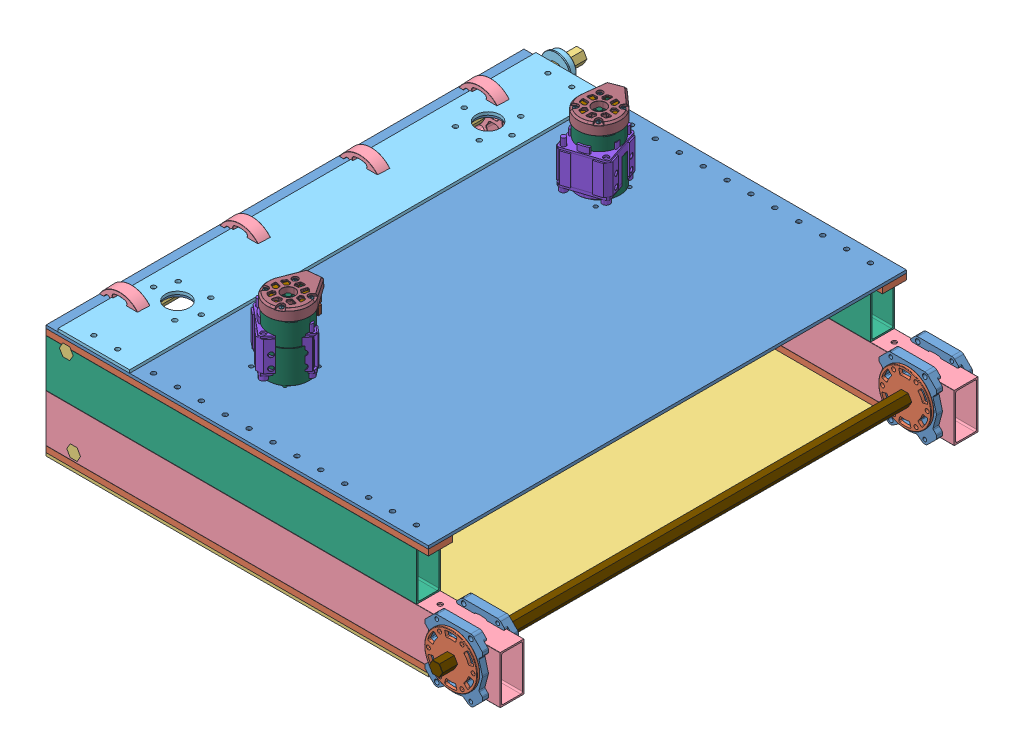
SolidWorks assembly top down new Shooter Assembly, configuration Default. Lengths in mm.
Overall size (495.19 207.94 571.5).
76 component instances, 24 part files, 95 mates.
Components (placement in the parent):
- ShooterPlate5-1: ShooterPlate5 [Default] at (-92.3523 376.6959 643.1212) size (406.4 3.17 508)
- ThickStick-3: ThickStick [Default] at (-92.3523 262.3959 643.1212) size (406.4 6.35 25.4)
- ThickStick-1: ThickStick [Default] at (-92.3523 370.3459 643.1212) size (406.4 6.35 25.4)
- ThickStick-2: ThickStick [Default] at (-92.3523 262.3959 160.5212) size (406.4 6.35 25.4)
- ThickStick-4: ThickStick [Default] at (-92.3523 370.3459 160.5212) size (406.4 6.35 25.4)
- ShooterPlate4-1: ShooterPlate4 [Default] at (-257.4523 259.2209 643.1212) size (406.4 3.17 508)
- side-1: side [Default] at (364.8477 294.1459 147.8212) x (0 0 1) z (-1 0 0) size (25.4 50.8 482.6)
- side-2: side [Default] at (364.8477 294.1459 630.4212) x (0 0 1) z (-1 0 0) size (25.4 50.8 482.6)
- Motor support2-1: Motor support2 [Default] at (-41.5523 379.8709 389.1212) x (0 0 1) z (-1 0 0) size (508 3.17 76.2)
- 4in hex stealth wheel-2: 4in hex stealth wheel [Default] at (72.733 290.5093 554.2466) x (0 -1 0) z (-0.5 0 0.866025) size (25.4 101.6 101.6)
  - 4in Wheel Intergreated Hub 500 HEX.STEP-1: 4in Wheel Intergreated Hub 500 HEX.STEP [Default] at origin size (25.4 92.71 92.71)
  - 4in Tread.STEP-1: 4in Tread.STEP [Default] at origin size (25.4 101.6 101.6)
- 4in hex stealth wheel-3: 4in hex stealth wheel [Default] at (72.7282 290.5093 224.043) x (0 -1 0) z (0.312488 0 0.949922) size (25.4 101.6 101.6)
  - 4in Wheel Intergreated Hub 500 HEX.STEP-1: 4in Wheel Intergreated Hub 500 HEX.STEP [Default] at origin size (25.4 92.71 92.71)
  - 4in Tread.STEP-1: 4in Tread.STEP [Default] at origin size (25.4 101.6 101.6)
- 4-1 Banebots-1: 4-1 Banebots [Default] at (72.7474 422.4159 224.0202) x (-0.312488 0 -0.949922) z (0 -1 0) size (47.62 47.62 76.19)
- 4-1 Banebots-2: 4-1 Banebots [Default] at (72.7471 422.4159 554.2219) x (-0.638444 0 0.769669) z (0 -1 0) size (47.62 47.62 76.19)
- 775pro.step-1: 775pro.step [Default] at (71.7936 373.6479 219.2017) x (-0.934395 0 0.356239) z (0 -1 0) size (44.99 55.15 90.45)
  - 217-6457-000 Rev2.step-1: 217-6457-000 Rev2.step [Default] at (0 0 -66.1) x (1 0 0) z (0 1 0) size (44.99 33.26 55.15)
    - 217-6457-900 Rev1.step-1: 217-6457-900 Rev1.step [Default] at (0 5.3622 0) x (-1 0 0.000693) z (0.000693 0 1) size (41.5 28.13 51.51)
      - 217-6457-901 Rev3_Instruction Config.step-1: 217-6457-901 Rev3_Instruction Config.step [Default] at origin size (41.5 2.36 51.5)
      - 30-45BBS Rev1_SHORTENED CONTACT.step-1: 30-45BBS Rev1_SHORTENED CONTACT.step [Default] at (3.95 14.4494 26.711) x (0 1 0) z (0 0 -1) size (26 3.6 2)
      - 30-45BBS Rev1_SHORTENED CONTACT.step-2: 30-45BBS Rev1_SHORTENED CONTACT.step [Default] at (-3.9748 14.4494 26.711) x (0 1 0) z (0 0 -1) size (26 3.6 2)
      - PA45XX-X Rev1.step-1: PA45XX-X Rev1.step [Default] at (-8.4198 2.3622 73.1531) x (0 1 0) z (-1 0 0) size (24.71 8.41 8.41)
      - PA45XX-X Rev1.step-2: PA45XX-X Rev1.step [Default] at (-0.495 2.3622 73.1531) x (0 1 0) z (-1 0 0) size (24.71 8.41 8.41)
    - 217-6457-001 Rev4.step-1: 217-6457-001 Rev4.step [Default] at origin size (41.49 7.8 41.49)
    - 217-6457-002 Rev7.step-1: 217-6457-002 Rev7.step [Default] at (0 0.05 0) size (44.99 11.5 55.15)
    - 217-9191-008 Rev1.step-1: 217-9191-008 Rev1.step [Default] at (81.4247 7.8 32.3804) x (-0.560945 0 -0.827853) z (0 1 0) size (4.2 4.2 11.81)
    - 217-9191-008 Rev1.step-2: 217-9191-008 Rev1.step [Default] at (32.3804 7.8 -81.4247) x (-0.827853 0 0.560945) z (0 1 0) size (4.2 4.2 11.81)
    - 217-9191-008 Rev1.step-3: 217-9191-008 Rev1.step [Default] at (-81.4247 7.8 -32.3804) x (0.560945 0 0.827853) z (0 1 0) size (4.2 4.2 11.81)
    - 217-9191-008 Rev1.step-4: 217-9191-008 Rev1.step [Default] at (-32.3804 7.8 81.4247) x (0.827853 0 -0.560945) z (0 1 0) size (4.2 4.2 11.81)
  - 217-4347-000 Rev2.step-1: 217-4347-000 Rev2.step [Default] x (0 0 -1) z (-1 0 0) size (88 44.3 44.3)
- 775pro.step-2: 775pro.step [Default] at (77.5101 373.6479 555.4281) x (-0.994351 0 0.106139) z (0 -1 0) size (44.99 55.15 90.45)
  - 217-6457-000 Rev2.step-1: 217-6457-000 Rev2.step [Default] at (0 0 -66.1) x (1 0 0) z (0 1 0) size (44.99 33.26 55.15)
    - 217-6457-900 Rev1.step-1: 217-6457-900 Rev1.step [Default] at (0 5.3622 0) x (-1 0 0.000693) z (0.000693 0 1) size (41.5 28.13 51.51)
      - 217-6457-901 Rev3_Instruction Config.step-1: 217-6457-901 Rev3_Instruction Config.step [Default] at origin size (41.5 2.36 51.5)
      - 30-45BBS Rev1_SHORTENED CONTACT.step-1: 30-45BBS Rev1_SHORTENED CONTACT.step [Default] at (3.95 14.4494 26.711) x (0 1 0) z (0 0 -1) size (26 3.6 2)
      - 30-45BBS Rev1_SHORTENED CONTACT.step-2: 30-45BBS Rev1_SHORTENED CONTACT.step [Default] at (-3.9748 14.4494 26.711) x (0 1 0) z (0 0 -1) size (26 3.6 2)
      - PA45XX-X Rev1.step-1: PA45XX-X Rev1.step [Default] at (-8.4198 2.3622 73.1531) x (0 1 0) z (-1 0 0) size (24.71 8.41 8.41)
      - PA45XX-X Rev1.step-2: PA45XX-X Rev1.step [Default] at (-0.495 2.3622 73.1531) x (0 1 0) z (-1 0 0) size (24.71 8.41 8.41)
    - 217-6457-001 Rev4.step-1: 217-6457-001 Rev4.step [Default] at origin size (41.49 7.8 41.49)
    - 217-6457-002 Rev7.step-1: 217-6457-002 Rev7.step [Default] at (0 0.05 0) size (44.99 11.5 55.15)
    - 217-9191-008 Rev1.step-1: 217-9191-008 Rev1.step [Default] at (81.4247 7.8 32.3804) x (-0.560945 0 -0.827853) z (0 1 0) size (4.2 4.2 11.81)
    - 217-9191-008 Rev1.step-2: 217-9191-008 Rev1.step [Default] at (32.3804 7.8 -81.4247) x (-0.827853 0 0.560945) z (0 1 0) size (4.2 4.2 11.81)
    - 217-9191-008 Rev1.step-3: 217-9191-008 Rev1.step [Default] at (-81.4247 7.8 -32.3804) x (0.560945 0 0.827853) z (0 1 0) size (4.2 4.2 11.81)
    - 217-9191-008 Rev1.step-4: 217-9191-008 Rev1.step [Default] at (-32.3804 7.8 81.4247) x (0.827853 0 -0.560945) z (0 1 0) size (4.2 4.2 11.81)
  - 217-4347-000 Rev2.step-1: 217-4347-000 Rev2.step [Default] x (0 0 -1) z (-1 0 0) size (88 44.3 44.3)
- 4in hex shaft-1: 4in hex shaft [Default] at (72.7477 381.6489 224.0212) x (0.666412 0 -0.745583) z (0 -1 0) size (14.66 12.7 101.6)
- 4in hex shaft-2: 4in hex shaft [Default] at (72.7477 381.6489 554.2212) x (-0.638444 0 0.769669) z (0 -1 0) size (14.66 12.7 101.6)
- am-2986 FR8ZZ Hex Bearing.step-1: am-2986 FR8ZZ Hex Bearing.step [Default] at (72.7477 255.9925 554.2212) x (0.638444 0 -0.769669) z (0 1 0) size (31.12 31.12 7.93)
- am-2986 FR8ZZ Hex Bearing.step-2: am-2986 FR8ZZ Hex Bearing.step [Default] at (72.7477 373.4675 554.2212) x (1 0 0) z (0 1 0) size (31.12 31.12 7.93)
- am-2986 FR8ZZ Hex Bearing.step-3: am-2986 FR8ZZ Hex Bearing.step [Default] at (72.7477 373.4675 224.0212) x (0.312488 0 0.949922) z (0 1 0) size (31.12 31.12 7.93)
- am-2986 FR8ZZ Hex Bearing.step-4: am-2986 FR8ZZ Hex Bearing.step [Default] at (72.7477 255.9925 224.0212) x (0.9789 0 0.204338) z (0 1 0) size (31.12 31.12 7.93)
- shooteraxle-1: shooteraxle [Default] at (347.36 295.7842 109.7212) size (14.66 12.7 558.8)
- VersaBlock V2 (217-6111).step-1: VersaBlock V2 (217-6111).step [Default] at (347.3674 295.7969 131.9462) x (1 0 0) z (0 0 -1) size (61.04 66.67 9.53)
- VersaBlock V2 (217-6111).step-2: VersaBlock V2 (217-6111).step [Default] at (347.3674 295.7969 614.5462) x (1 0 0) z (0 0 -1) size (61.04 66.67 9.53)
- VersaBlock V2 (217-6111).step-3: VersaBlock V2 (217-6111).step [Default] at (347.3674 295.7969 646.2962) x (-1 0 0) z (0 0 1) size (61.04 66.67 9.53)
- VersaBlock V2 (217-6111).step-4: VersaBlock V2 (217-6111).step [Default] at (347.3674 295.7969 163.6962) x (-1 0 0) z (0 0 1) size (61.04 66.67 9.53)
- 1_2” Hex Bore Aluminum VersaHub (217-2592).step-1: 1_2” Hex Bore Aluminum VersaHub (217-2592).step [Default] at (347.3674 295.7969 138.2962) x (0 0 -1) z (0.866025 -0.5 0) size (12.7 55.88 55.88)
- 1_2” Hex Bore Aluminum VersaHub (217-2592).step-2: 1_2” Hex Bore Aluminum VersaHub (217-2592).step [Default] at (347.3674 295.7969 157.3462) x (0 0 1) z (-0.866025 -0.5 0) size (12.7 55.88 55.88)
- 1_2” Hex Bore Aluminum VersaHub (217-2592).step-3: 1_2” Hex Bore Aluminum VersaHub (217-2592).step [Default] at (347.3674 295.7969 620.8962) x (0 0 -1) z (0.866025 0.5 0) size (12.7 55.88 55.88)
- 1_2” Hex Bore Aluminum VersaHub (217-2592).step-4: 1_2” Hex Bore Aluminum VersaHub (217-2592).step [Default] at (347.3674 295.7969 639.9462) x (0 0 1) z (-0.866025 0.5 0) size (12.7 55.88 55.88)
- axel and wheels for top down new Shooter design-1: axel and wheels for top down new Shooter design [Default] at origin size (69.37 69.37 546.1)
  - .5in hex shaft 21.5in-1: .5in hex shaft 21.5in [Default] at (-70.8055 365.9874 135.1212) size (14.66 12.7 546.1)
  - 2in complient wheel-1: 2in complient wheel [Default] at (-70.2556 366.9399 192.2712) x (0.5 -0.866025 0) z (0 0 1) size (50.78 50.78 12.7)
  - 2in complient wheel-2: 2in complient wheel [Default] at (-70.2556 366.9399 446.2712) size (50.78 50.78 12.7)
  - 2in complient wheel-3: 2in complient wheel [Default] at (-71.3555 366.9399 573.2712) size (50.78 50.78 12.7)
  - 2in complient wheel-4: 2in complient wheel [Default] at (-70.2556 366.9399 319.2712) size (50.78 50.78 12.7)
- 2in complient wheel-5: 2in complient wheel [Default] at (-62.4291 278.0399 319.2712) size (50.78 50.78 12.7)
- 2in complient wheel-6: 2in complient wheel [Default] at (-62.4291 278.0399 446.2712) size (50.78 50.78 12.7)
- 2in complient wheel-7: 2in complient wheel [Default] at (-63.529 278.0399 573.2712) size (50.78 50.78 12.7)
- 2in complient wheel-8: 2in complient wheel [Default] at (-62.4291 278.0399 192.2712) x (0.5 -0.866025 0) z (0 0 1) size (50.78 50.78 12.7)
- .5in hex shaft 21.5in-2: .5in hex shaft 21.5in [Default] at (-62.9791 277.0874 135.1212) size (14.66 12.7 546.1)
- Hex Bearing-1: Hex Bearing [Default] at (-70.8055 365.9874 115.1734) size (31.12 31.12 7.93)
- side short v2-1: side short v2 [Default] at (390.2477 344.9459 630.4212) x (0 0 1) z (-1 0 0) size (25.4 50.8 393.7)
- side short v2-2: side short v2 [Default] at (390.2477 344.9459 147.8212) x (0 0 1) z (-1 0 0) size (25.4 50.8 393.7)
Mates (geometry in assembly coordinates):
- Coincident2: coincident aligned: plane of ShooterPlate5-1 through (-92.3523 379.8709 643.1212) normal (-1 0 0); plane of side-2 through (-92.3523 319.2919 642.8672) normal (-1 0 0)
- Coincident5: coincident aligned: plane of ShooterPlate5-1 through (314.0477 379.8709 643.1212) normal (1 0 0); plane of ThickStick-1 through (314.0477 376.6959 643.1212) normal (1 0 0)
- Coincident6: coincident aligned: plane of ShooterPlate5-1 through (-92.3523 379.8709 643.1212) normal (0 0 1); plane of ThickStick-1 through (-92.3523 376.6959 643.1212) normal (0 0 1)
- Coincident8: coincident anti-aligned: plane of ThickStick-3 through (-92.3523 268.7459 643.1212) normal (0 1 0); plane of side-2 through (390.2477 268.7459 642.8672) normal (0 -1 0)
- Coincident9: coincident aligned: plane of ThickStick-3 through (-92.3523 268.7459 643.1212) normal (0 0 1); plane of side-2 through (390.2477 319.2919 643.1212) normal (0 0 1)
- Coincident11: coincident aligned: plane of ThickStick-1 through (-92.3523 376.6959 643.1212) normal (-1 0 0); plane of ThickStick-3 through (-92.3523 268.7459 643.1212) normal (-1 0 0)
- Coincident12: coincident anti-aligned: plane of ThickStick-3 through (-92.3523 262.3959 643.1212) normal (0 -1 0); plane of ShooterPlate4-1 through (-257.4523 262.3959 643.1212) normal (0 1 0)
- Coincident13: coincident aligned: plane of ShooterPlate5-1 through (-92.3523 379.8709 643.1212) normal (0 0 1); plane of ShooterPlate4-1 through (-257.4523 262.3959 643.1212) normal (0 0 1)
- Coincident14: coincident aligned: plane of ThickStick-3 through (314.0477 268.7459 643.1212) normal (1 0 0); plane of ShooterPlate4-1 through (314.0477 262.3959 643.1212) normal (1 0 0)
- Coincident16: coincident aligned: plane of ShooterPlate5-1 through (-92.3523 379.8709 643.1212) normal (-1 0 0); plane of ThickStick-4 through (-92.3523 376.6959 160.5212) normal (-1 0 0)
- Coincident18: coincident aligned: plane of ShooterPlate5-1 through (-92.3523 379.8709 135.1212) normal (0 0 -1); plane of ThickStick-4 through (-92.3523 376.6959 135.1212) normal (0 0 -1)
- Coincident19: coincident aligned: plane of ThickStick-4 through (-92.3523 376.6959 135.1212) normal (0 0 -1); plane of side-1 through (390.2477 268.9999 135.1212) normal (0 0 -1)
- Coincident20: coincident aligned: plane of ThickStick-4 through (-92.3523 376.6959 160.5212) normal (-1 0 0); plane of side-1 through (-92.3523 319.2919 160.2672) normal (-1 0 0)
- Coincident21: coincident anti-aligned: plane of ThickStick-2 through (-92.3523 262.3959 160.5212) normal (0 -1 0); plane of ShooterPlate4-1 through (-257.4523 262.3959 643.1212) normal (0 1 0)
- Coincident22: coincident aligned: plane of ThickStick-2 through (-92.3523 268.7459 135.1212) normal (0 0 -1); plane of side-1 through (390.2477 268.9999 135.1212) normal (0 0 -1)
- Coincident23: coincident aligned: plane of ShooterPlate5-1 through (-92.3523 379.8709 643.1212) normal (-1 0 0); plane of ThickStick-2 through (-92.3523 268.7459 160.5212) normal (-1 0 0)
- Coincident24: coincident anti-aligned: plane of ShooterPlate5-1 through (-92.3523 379.8709 643.1212) normal (0 1 0); plane of Motor support2-1 through (-41.5523 379.8709 389.1212) normal (0 -1 0)
- Coincident25: coincident aligned: plane of side-1 through (390.2477 268.9999 135.1212) normal (0 0 -1); plane of Motor support2-1 through (-79.6523 383.0459 135.1212) normal (0 0 -1)
- Concentric1: concentric aligned: cylinder of ShooterPlate5-1 through (-41.5523 376.6959 224.0212) axis (0 1 0) radius 14.2875; cylinder of Motor support2-1 through (-41.5523 379.8709 224.0212) axis (0 1 0) radius 12.7
- Concentric10: concentric anti-aligned: cylinder of ShooterPlate5-1 through (72.7477 376.6959 224.0212) axis (0 1 0) radius 14.2875; cylinder of am-2986 FR8ZZ Hex Bearing.step-3 through (72.7477 381.3949 224.0212) axis (0 -1 0) radius 14.2875
- Coincident39: coincident anti-aligned: plane of ShooterPlate5-1 through (-92.3523 379.8709 643.1212) normal (0 1 0); plane of am-2986 FR8ZZ Hex Bearing.step-3 through (77.1132 379.8709 237.2916) normal (0 -1 0)
- Concentric11: concentric anti-aligned: cylinder of ShooterPlate5-1 through (72.7477 376.6959 554.2212) axis (0 1 0) radius 14.2875; cylinder of am-2986 FR8ZZ Hex Bearing.step-2 through (72.7477 381.3949 554.2212) axis (0 -1 0) radius 14.2875
- Coincident40: coincident anti-aligned: plane of ShooterPlate5-1 through (-92.3523 379.8709 643.1212) normal (0 1 0); plane of am-2986 FR8ZZ Hex Bearing.step-2 through (86.7177 379.8709 554.2212) normal (0 -1 0)
- Concentric12: concentric anti-aligned: cylinder of ShooterPlate4-1 through (72.7477 259.2209 554.2212) axis (0 1 0) radius 14.2875; cylinder of am-2986 FR8ZZ Hex Bearing.step-1 through (72.7477 263.9199 554.2212) axis (0 -1 0) radius 14.2875
- Coincident41: coincident anti-aligned: plane of ShooterPlate4-1 through (-257.4523 262.3959 643.1212) normal (0 1 0); plane of am-2986 FR8ZZ Hex Bearing.step-1 through (81.6668 262.3959 543.4689) normal (0 -1 0)
- Concentric13: concentric anti-aligned: cylinder of ShooterPlate4-1 through (72.7477 259.2209 224.0212) axis (0 1 0) radius 14.2875; cylinder of am-2986 FR8ZZ Hex Bearing.step-4 through (72.7477 263.9199 224.0212) axis (0 -1 0) radius 14.2875
- Coincident42: coincident anti-aligned: plane of ShooterPlate4-1 through (-257.4523 262.3959 643.1212) normal (0 1 0); plane of am-2986 FR8ZZ Hex Bearing.step-4 through (86.4229 262.3959 226.8758) normal (0 -1 0)
- Coincident44: coincident anti-aligned: plane of 4-1 Banebots-1 through (67.8613 381.6559 229.488) normal (-0.949922 0 0.312488); plane of am-2986 FR8ZZ Hex Bearing.step-3 through (67.8613 381.3949 229.488) normal (0.949922 0 -0.312488)
- Coincident53: coincident anti-aligned: plane of 4in hex shaft-2 through (75.2945 280.0489 561.097) normal (0.769669 0 0.638444); plane of am-2986 FR8ZZ Hex Bearing.step-1 through (79.9758 263.9199 555.4535) normal (-0.769669 0 -0.638444)
- Coincident54: coincident anti-aligned: plane of 4in hex shaft-2 through (68.0664 280.0489 559.8646) normal (-0.168074 0 0.985774); plane of am-2986 FR8ZZ Hex Bearing.step-1 through (75.2945 263.9199 561.097) normal (0.168074 0 -0.985774)
- Tangent9: tangent: plane of assembly; face of 4-1 Banebots-2; plane of 4in hex shaft-2 through (72.7477 381.6489 554.2212) normal (0 1 0)
- Coincident55: coincident aligned: plane of 4-1 Banebots-2 through (68.0664 381.6559 559.8646) normal (-0.937743 0 0.347331); plane of 4in hex shaft-2 through (65.5197 280.0489 552.9888) normal (-0.937743 0 0.347331)
- Coincident56: coincident aligned: plane of 4-1 Banebots-2 through (65.5197 381.6559 552.9888) normal (-0.769669 0 -0.638444); plane of 4in hex shaft-2 through (70.201 280.0489 547.3453) normal (-0.769669 0 -0.638444)
- Tangent10: tangent: plane of assembly; face of 4-1 Banebots-2; plane of am-2986 FR8ZZ Hex Bearing.step-2 through (88.3052 381.3949 554.2212) normal (0 1 0)
- Tangent11: tangent: plane of assembly; face of 4-1 Banebots-1; plane of 4in hex shaft-1 through (72.7477 381.6489 224.0212) normal (0 1 0)
- Coincident57: coincident aligned: plane of 4-1 Banebots-1 through (65.5701 381.6559 222.5229) normal (-0.745583 0 -0.666412); plane of 4in hex shaft-1 through (70.4564 280.0489 217.056) normal (-0.745583 0 -0.666412)
- Coincident58: coincident aligned: plane of 4-1 Banebots-1 through (67.8613 381.6559 229.488) normal (-0.949922 0 0.312488); plane of 4in hex shaft-1 through (65.5701 280.0489 222.5229) normal (-0.949922 0 0.312488)
- Tangent12: tangent: plane of assembly; face of 4-1 Banebots-1; plane of am-2986 FR8ZZ Hex Bearing.step-3 through (77.6092 381.3949 238.7996) normal (0 1 0)
- Coincident60: coincident anti-aligned: plane of 4in hex shaft-1 through (79.9253 280.0489 225.5194) normal (0.949922 0 -0.312488); plane of am-2986 FR8ZZ Hex Bearing.step-4 through (77.6341 263.9199 218.5543) normal (-0.949922 0 0.312488)
- Coincident61: coincident anti-aligned: plane of 4in hex shaft-1 through (75.039 280.0489 230.9863) normal (0.745583 0 0.666412); plane of am-2986 FR8ZZ Hex Bearing.step-4 through (79.9253 263.9199 225.5194) normal (-0.745583 0 -0.666412)
- Coincident62: coincident anti-aligned: plane of 4in hex stealth wheel-3/4in Wheel Intergreated Hub 500 HEX.STEP-1 through (70.4277 304.4334 217.05) normal (-0.204338 0 0.9789); plane of 4in hex shaft-1 through (77.6341 280.0489 218.5543) normal (0.204338 0 -0.9789)
- Coincident63: coincident anti-aligned: plane of 4in hex stealth wheel-3/4in Wheel Intergreated Hub 500 HEX.STEP-1 through (77.6341 304.4334 218.5543) normal (-0.949922 0 0.312488); plane of 4in hex shaft-1 through (79.9253 280.0489 225.5194) normal (0.949922 0 -0.312488)
- Distance1: distance = 25.4 mm aligned: plane of side-1 through (390.2477 268.9999 135.1212) normal (0 0 -1); plane of shooteraxle-1 through (347.36 295.7842 109.7212) normal (0 0 -1)
- Coincident72: coincident anti-aligned: plane of side-2 through (390.2477 319.2919 643.1212) normal (0 0 1); plane of VersaBlock V2 (217-6111).step-3 through (347.3674 295.7969 643.1212) normal (0 0 -1)
- Coincident73: coincident anti-aligned: plane of side-2 through (390.2477 268.7459 642.8672) normal (0 -1 0); plane of VersaBlock V2 (217-6111).step-3 through (316.8493 268.7459 722.6131) normal (0 1 0)
- Tangent13: tangent aligned: cylinder of side-2 through (345.7977 295.9239 643.1212) axis (0 0 -1) radius 12.7; cylinder of VersaBlock V2 (217-6111).step-3 through (347.3674 295.7969 604.2621) axis (0 0 1) radius 14.2748
- Coincident74: coincident anti-aligned: plane of side-2 through (390.2477 268.9999 617.7212) normal (0 0 -1); plane of VersaBlock V2 (217-6111).step-2 through (347.3674 295.7969 617.7212) normal (0 0 1)
- Coincident75: coincident anti-aligned: plane of side-2 through (390.2477 268.7459 642.8672) normal (0 -1 0); plane of VersaBlock V2 (217-6111).step-2 through (377.8855 268.7459 538.2292) normal (0 1 0)
- Concentric24: concentric anti-aligned: cylinder of VersaBlock V2 (217-6111).step-2 through (365.4542 323.1543 620.8962) axis (0 0 1) radius 2.0193; cylinder of VersaBlock V2 (217-6111).step-3 through (365.4542 323.1543 639.9462) axis (0 0 -1) radius 2.4892
- Coincident76: coincident anti-aligned: plane of side-1 through (390.2477 268.9999 135.1212) normal (0 0 -1); plane of VersaBlock V2 (217-6111).step-1 through (347.3674 295.7969 135.1212) normal (0 0 1)
- Coincident77: coincident anti-aligned: plane of side-1 through (390.2477 268.7459 160.2672) normal (0 -1 0); plane of VersaBlock V2 (217-6111).step-1 through (377.8855 268.7459 55.6292) normal (0 1 0)
- Tangent14: tangent aligned: cylinder of side-1 through (345.7977 295.9239 160.5212) axis (0 0 -1) radius 12.7; cylinder of VersaBlock V2 (217-6111).step-1 through (347.3674 295.7969 173.9802) axis (0 0 -1) radius 14.2748
- Coincident78: coincident anti-aligned: plane of side-1 through (390.2477 268.7459 160.2672) normal (0 -1 0); plane of VersaBlock V2 (217-6111).step-4 through (316.8493 268.7459 240.0131) normal (0 1 0)
- Coincident79: coincident anti-aligned: plane of side-1 through (390.2477 319.2919 160.5212) normal (0 0 1); plane of VersaBlock V2 (217-6111).step-4 through (347.3674 295.7969 160.5212) normal (0 0 -1)
- Concentric26: concentric anti-aligned: cylinder of VersaBlock V2 (217-6111).step-1 through (365.4542 323.1543 138.2962) axis (0 0 1) radius 2.0193; cylinder of VersaBlock V2 (217-6111).step-4 through (365.4542 323.1543 157.3462) axis (0 0 -1) radius 2.4892
- Coincident80: coincident anti-aligned: plane of VersaBlock V2 (217-6111).step-3 through (359.2736 316.4191 649.4712) normal (0 0 1); plane of 1_2” Hex Bore Aluminum VersaHub (217-2592).step-4 through (354.5148 308.1766 649.4712) normal (0 0 -1)
- Concentric30: concentric aligned: cylinder of VersaBlock V2 (217-6111).step-3 through (335.4611 316.4191 649.4712) axis (0 0 1) radius 1.7272; cylinder of 1_2” Hex Bore Aluminum VersaHub (217-2592).step-4 through (335.4611 316.4191 566.8528) axis (0 0 1) radius 2.15
- Concentric31: concentric aligned: cylinder of VersaBlock V2 (217-6111).step-3 through (359.2736 316.4191 649.4712) axis (0 0 1) radius 1.7272; cylinder of 1_2” Hex Bore Aluminum VersaHub (217-2592).step-4 through (359.2736 316.4191 566.8528) axis (0 0 1) radius 2.15
- Coincident82: coincident anti-aligned: plane of VersaBlock V2 (217-6111).step-1 through (335.4611 316.4191 128.7712) normal (0 0 -1); plane of 1_2” Hex Bore Aluminum VersaHub (217-2592).step-1 through (354.5148 308.1766 128.7712) normal (0 0 1)
- Concentric32: concentric aligned: cylinder of VersaBlock V2 (217-6111).step-1 through (335.4611 316.4191 128.7712) axis (0 0 -1) radius 1.7272; cylinder of 1_2” Hex Bore Aluminum VersaHub (217-2592).step-1 through (335.4611 316.4191 211.3895) axis (0 0 -1) radius 2.15
- Concentric33: concentric aligned: cylinder of VersaBlock V2 (217-6111).step-1 through (359.2736 316.4191 128.7712) axis (0 0 -1) radius 1.7272; cylinder of 1_2” Hex Bore Aluminum VersaHub (217-2592).step-1 through (359.2736 316.4191 211.3895) axis (0 0 -1) radius 2.15
- Coincident83: coincident anti-aligned: plane of VersaBlock V2 (217-6111).step-4 through (359.2736 316.4191 166.8712) normal (0 0 1); plane of 1_2” Hex Bore Aluminum VersaHub (217-2592).step-2 through (340.2199 308.1766 166.8712) normal (0 0 -1)
- Concentric35: concentric aligned: cylinder of VersaBlock V2 (217-6111).step-4 through (359.2736 316.4191 166.8712) axis (0 0 1) radius 1.7272; cylinder of 1_2” Hex Bore Aluminum VersaHub (217-2592).step-2 through (359.2736 316.4191 84.2528) axis (0 0 1) radius 2.15
- Concentric36: concentric aligned: cylinder of VersaBlock V2 (217-6111).step-4 through (335.4611 316.4191 166.8712) axis (0 0 1) radius 1.7272; cylinder of 1_2” Hex Bore Aluminum VersaHub (217-2592).step-2 through (335.4611 316.4191 84.2528) axis (0 0 1) radius 2.15
- Coincident84: coincident anti-aligned: plane of VersaBlock V2 (217-6111).step-2 through (335.4611 316.4191 611.3712) normal (0 0 -1); plane of 1_2” Hex Bore Aluminum VersaHub (217-2592).step-3 through (340.2199 308.1766 611.3712) normal (0 0 1)
- Concentric37: concentric aligned: cylinder of VersaBlock V2 (217-6111).step-2 through (359.2736 316.4191 611.3712) axis (0 0 -1) radius 1.7272; cylinder of 1_2” Hex Bore Aluminum VersaHub (217-2592).step-3 through (359.2736 316.4191 693.9895) axis (0 0 -1) radius 2.15
- Concentric38: concentric aligned: cylinder of VersaBlock V2 (217-6111).step-2 through (335.4611 316.4191 611.3712) axis (0 0 -1) radius 1.7272; cylinder of 1_2” Hex Bore Aluminum VersaHub (217-2592).step-3 through (335.4611 316.4191 693.9895) axis (0 0 -1) radius 2.15
- Coincident85: coincident anti-aligned: plane of shooteraxle-1 through (351.0262 289.4342 668.5212) normal (0 -1 0); plane of 1_2” Hex Bore Aluminum VersaHub (217-2592).step-4 through (343.6939 289.4342 639.9462) normal (0 1 0)
- Coincident86: coincident anti-aligned: plane of shooteraxle-1 through (343.6939 289.4342 668.5212) normal (-0.866025 -0.5 0); plane of 1_2” Hex Bore Aluminum VersaHub (217-2592).step-4 through (340.0204 295.7969 639.9462) normal (0.866025 0.5 0)
- Coincident105: coincident anti-aligned: plane of 2in complient wheel-8 through (-59.3129 283.4374 192.213) normal (0 -1 0); plane of .5in hex shaft 21.5in-2 through (-59.3129 283.4374 97.0212) normal (0 1 0)
- Coincident106: coincident anti-aligned: plane of 2in complient wheel-8 through (-56.1966 278.0399 192.213) normal (-0.866025 -0.5 0); plane of .5in hex shaft 21.5in-2 through (-55.6467 277.0874 97.0212) normal (0.866025 0.5 0)
- Coincident107: coincident anti-aligned: plane of 2in complient wheel-7 through (-66.6452 283.4374 573.213) normal (0.866025 -0.5 0); plane of .5in hex shaft 21.5in-2 through (-66.6452 283.4374 97.0212) normal (-0.866025 0.5 0)
- Coincident108: coincident anti-aligned: plane of 2in complient wheel-6 through (-59.3129 283.4374 446.213) normal (0 -1 0); plane of .5in hex shaft 21.5in-2 through (-59.3129 283.4374 97.0212) normal (0 1 0)
- Coincident109: coincident anti-aligned: plane of 2in complient wheel-5 through (-59.3129 283.4374 319.213) normal (0 -1 0); plane of .5in hex shaft 21.5in-2 through (-59.3129 283.4374 97.0212) normal (0 1 0)
- Distance6: distance = 184.15 mm aligned: plane of 2in complient wheel-6 through (-62.4291 278.0399 458.9712) normal (0 0 1); plane of .5in hex shaft 21.5in-2 through (-62.9791 277.0874 643.1212) normal (0 0 1)
- Distance7: distance = 57.15 mm aligned: plane of 2in complient wheel-7 through (-63.529 278.0399 585.9712) normal (0 0 1); plane of .5in hex shaft 21.5in-2 through (-62.9791 277.0874 643.1212) normal (0 0 1)
- Distance8: distance = 311.15 mm aligned: plane of 2in complient wheel-5 through (-62.4291 278.0399 331.9712) normal (0 0 1); plane of .5in hex shaft 21.5in-2 through (-62.9791 277.0874 643.1212) normal (0 0 1)
- Distance9: distance = 438.15 mm aligned: plane of 2in complient wheel-8 through (-62.4291 278.0399 204.9712) normal (0 0 1); plane of .5in hex shaft 21.5in-2 through (-62.9791 277.0874 643.1212) normal (0 0 1)
- Coincident110: coincident anti-aligned: plane of 2in complient wheel-6 through (-56.1966 278.0399 446.213) normal (-0.866025 -0.5 0); plane of .5in hex shaft 21.5in-2 through (-55.6467 277.0874 97.0212) normal (0.866025 0.5 0)
- Coincident111: coincident anti-aligned: plane of 2in complient wheel-5 through (-56.1966 278.0399 319.213) normal (-0.866025 -0.5 0); plane of .5in hex shaft 21.5in-2 through (-55.6467 277.0874 97.0212) normal (0.866025 0.5 0)
- Coincident112: coincident anti-aligned: plane of 2in complient wheel-7 through (-60.4127 283.4374 573.213) normal (0 -1 0); plane of .5in hex shaft 21.5in-2 through (-59.3129 283.4374 97.0212) normal (0 1 0)
- Distance10: distance = 38.1 mm aligned: plane of side-1 through (390.2477 268.9999 135.1212) normal (0 0 -1); plane of .5in hex shaft 21.5in-2 through (-62.9791 277.0874 97.0212) normal (0 0 -1)
- Coincident120: coincident anti-aligned: plane of side-1 through (390.2477 319.5459 135.3752) normal (0 1 0); plane of side short v2-2 through (-92.3523 319.5459 160.2672) normal (0 -1 0)
- Coincident121: coincident aligned: plane of side-1 through (390.2477 268.9999 135.1212) normal (0 0 -1); plane of side short v2-2 through (-92.3523 319.7999 135.1212) normal (0 0 -1)
- Coincident122: coincident aligned: plane of side-1 through (-92.3523 319.2919 160.2672) normal (-1 0 0); plane of side short v2-2 through (-92.3523 370.0919 160.2672) normal (-1 0 0)
- Coincident123: coincident anti-aligned: plane of side-2 through (390.2477 319.5459 617.9752) normal (0 1 0); plane of side short v2-1 through (-92.3523 319.5459 642.8672) normal (0 -1 0)
- Coincident124: coincident aligned: plane of side-2 through (390.2477 319.2919 643.1212) normal (0 0 1); plane of side short v2-1 through (-92.3523 370.0919 643.1212) normal (0 0 1)
- Coincident125: coincident aligned: plane of side-2 through (-92.3523 319.2919 642.8672) normal (-1 0 0); plane of side short v2-1 through (-92.3523 370.0919 642.8672) normal (-1 0 0)
- Coincident126: coincident anti-aligned: plane of ThickStick-4 through (-92.3523 370.3459 160.5212) normal (0 -1 0); plane of side short v2-2 through (-92.3523 370.3459 135.3752) normal (0 1 0)
- Coincident128: coincident anti-aligned: plane of ThickStick-1 through (-92.3523 370.3459 643.1212) normal (0 -1 0); plane of side short v2-1 through (-92.3523 370.3459 617.9752) normal (0 1 0)
- Coincident129: coincident anti-aligned: plane of ShooterPlate5-1 through (-92.3523 376.6959 643.1212) normal (0 -1 0); plane of ThickStick-1 through (-92.3523 376.6959 643.1212) normal (0 1 0)
- Distance14: distance = 38.1 mm aligned: plane of side-1 through (390.2477 268.9999 135.1212) normal (0 0 -1); plane of Assem1^top down new Shooter Assembly-1/.5in hex shaft 21.5in-1 through (-70.8055 365.9874 97.0212) normal (0 0 -1)
- Coincident130: coincident anti-aligned: plane of Assem1^top down new Shooter Assembly-1/.5in hex shaft 21.5in-1 through (-67.1394 372.3374 97.0212) normal (0 1 0); plane of Hex Bearing-1 through (-74.4717 372.3374 123.1007) normal (0 -1 0)
- Coincident131: coincident anti-aligned: plane of Assem1^top down new Shooter Assembly-1/.5in hex shaft 21.5in-1 through (-67.1394 359.6374 97.0212) normal (0.866025 -0.5 0); plane of Hex Bearing-1 through (-63.4732 365.9874 123.1007) normal (-0.866025 0.5 0)
- Distance15: distance = 76.2 mm anti-aligned: plane of Assem1^top down new Shooter Assembly-1/.5in hex shaft 21.5in-1 through (-74.4717 359.6374 97.0212) normal (0 -1 0); plane of .5in hex shaft 21.5in-2 through (-59.3129 283.4374 97.0212) normal (0 1 0)
